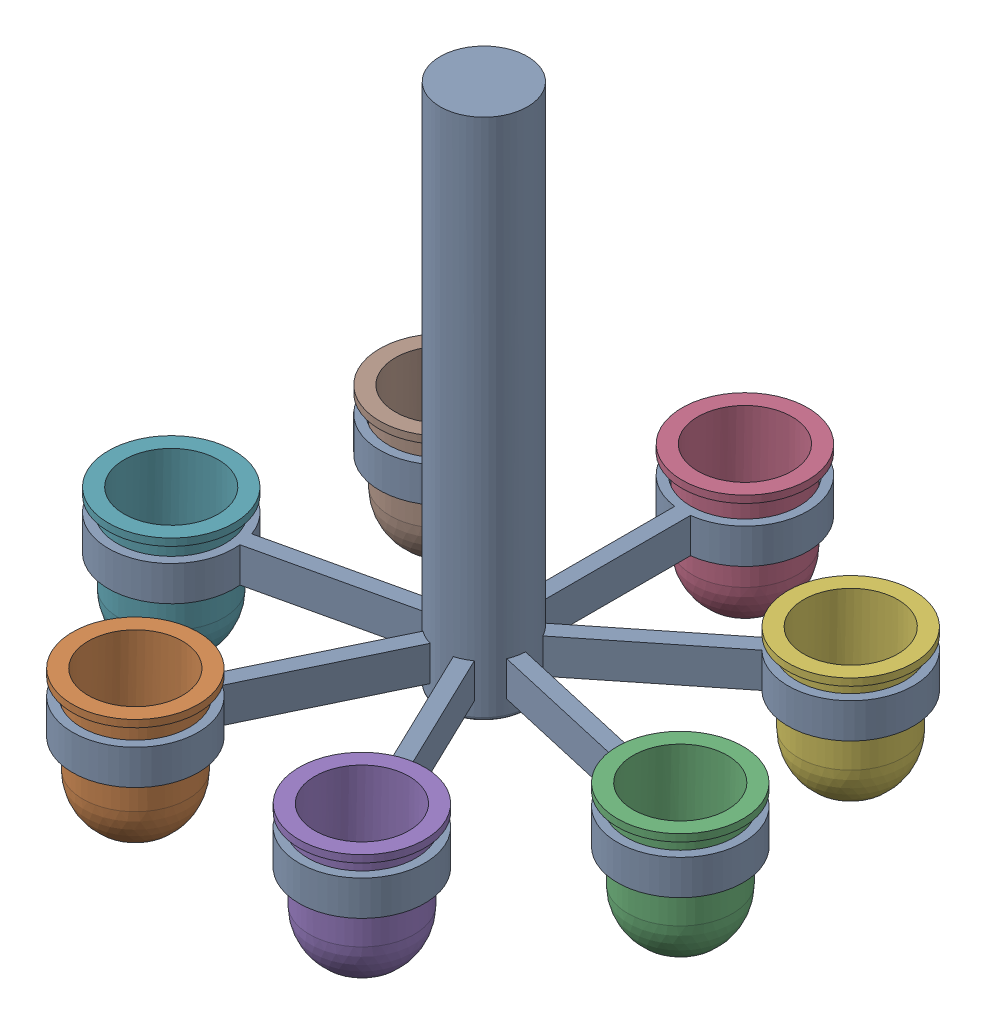
SolidWorks assembly Carousel_1_assembly, configuration Default. Lengths in mm.
Overall size (191.8 169.36 191.38).
8 component instances, 2 part files, 7 mates.
Components (placement in the parent):
- Carousel_1-1: Carousel_1 [Default] at (15.2418 -49.7908 28.3027) size (181.86 150 178.2)
- Container-2: Container [Default] at (-17.2152 -67.8972 95.7004) x (0.946972 0 -0.321316) z (0.321316 0 0.946972) size (35.97 40 35.97)
- Container-3: Container [Default] at (88.1719 -68.9397 44.9486) x (0.971004 0 -0.239063) z (0.239063 0 0.971004) size (35.97 40 35.97)
- Container-4: Container [Default] at (15.2418 -67.1013 -46.503) x (0.746605 0 -0.665268) z (0.665268 0 0.746605) size (35.97 40 35.97)
- Container-5: Container [Default] at (47.6987 -68.9963 95.7004) x (0.91191 0 -0.41039) z (0.41039 0 0.91191) size (35.97 40 35.97)
- Container-6: Container [Default] at (73.7272 -69.1485 -18.3379) x (0.853188 0 -0.521604) z (0.521604 0 0.853188) size (35.97 40 35.97)
- Container-7: Container [Default] at (-57.6884 -68.4946 44.9486) x (0.891605 0 -0.452813) z (0.452813 0 0.891605) size (35.97 40 35.97)
- Container-8: Container [Default] at (-43.2437 -67.5996 -18.3379) x (0.814542 0 -0.580105) z (0.580105 0 0.814542) size (35.97 40 35.97)
Mates (geometry in assembly coordinates):
- Concentric1: concentric anti-aligned: cylinder of Carousel_1-1 through (-17.2152 -34.7908 95.7004) axis (0 -1 0) radius 15.5; cylinder of Container-2 through (-17.2152 39.1804 95.7004) axis (0 1 0) radius 15
- Concentric2: concentric anti-aligned: cylinder of Carousel_1-1 through (47.6987 -34.7908 95.7004) axis (0 -1 0) radius 15.5; cylinder of Container-5 through (47.6987 38.0812 95.7004) axis (0 1 0) radius 15
- Concentric3: concentric anti-aligned: cylinder of Carousel_1-1 through (88.1719 -34.7908 44.9486) axis (0 -1 0) radius 15.5; cylinder of Container-3 through (88.1719 38.1378 44.9486) axis (0 1 0) radius 15
- Concentric4: concentric anti-aligned: cylinder of Carousel_1-1 through (73.7272 -34.7908 -18.3379) axis (0 -1 0) radius 15.5; cylinder of Container-6 through (73.7272 37.929 -18.3379) axis (0 1 0) radius 15
- Concentric5: concentric anti-aligned: cylinder of Carousel_1-1 through (15.2418 -34.7908 -46.503) axis (0 -1 0) radius 15.5; cylinder of Container-4 through (15.2418 39.9763 -46.503) axis (0 1 0) radius 15
- Concentric6: concentric anti-aligned: cylinder of Carousel_1-1 through (-43.2437 -34.7908 -18.3379) axis (0 -1 0) radius 15.5; cylinder of Container-8 through (-43.2437 39.478 -18.3379) axis (0 1 0) radius 15
- Concentric7: concentric anti-aligned: cylinder of Carousel_1-1 through (-57.6884 -34.7908 44.9486) axis (0 -1 0) radius 15.5; cylinder of Container-7 through (-57.6884 38.583 44.9486) axis (0 1 0) radius 15
